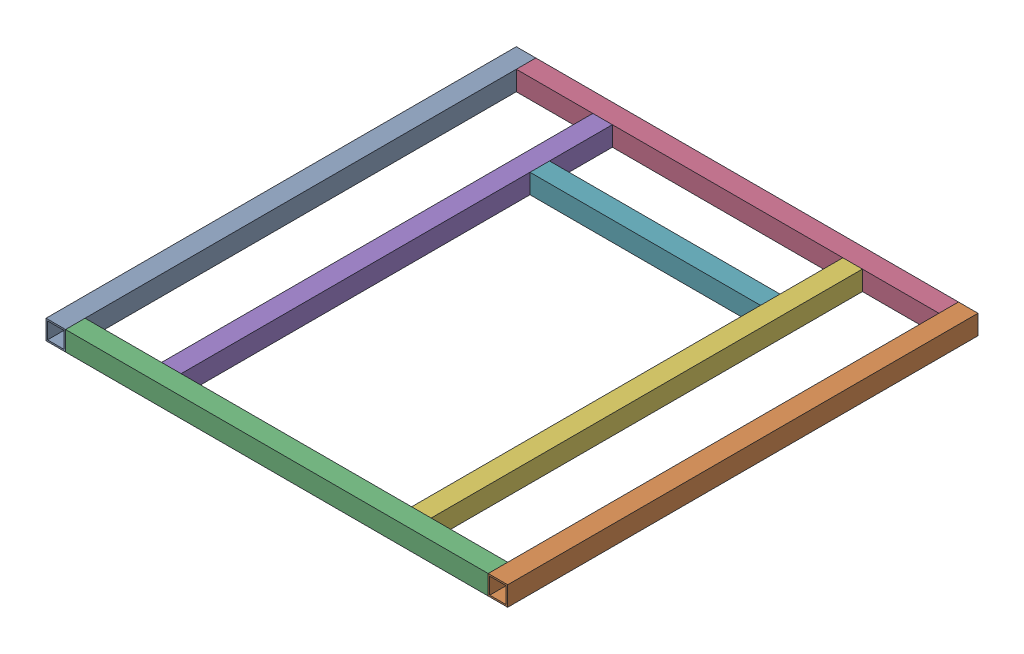
SolidWorks assembly Chassis_2_Frame_Assy, configuration Default. Lengths in mm.
Overall size (600.8 25.4 612).
7 component instances, 4 part files, 18 mates.
Components (placement in the parent):
- 1x1inch_612mmBeam-1: 1x1inch_612mmBeam [Default] at (-50.6735 117.5491 -53.1214) size (25.4 25.4 612)
- 1x1inch_612mmBeam-2: 1x1inch_612mmBeam [Default] at (524.7265 117.5491 -53.1214) size (25.4 25.4 612)
- 1x1inch_550mmBeam-1: 1x1inch_550mmBeam [Default] at (512.0265 117.5491 546.1786) x (0 0 -1) z (-1 0 0) size (25.4 25.4 550)
- 1x1inch_550mmBeam-2: 1x1inch_550mmBeam [Default] at (-37.9735 117.5491 -40.4214) x (0 0 1) z (1 0 0) size (25.4 25.4 550)
- 1x1inch_561.2mmBeam-1: 1x1inch_561.2mmBeam [Default] at (74.3265 117.5491 -27.7214) size (25.4 25.4 561.2)
- 1x1inch_561.2mmBeam-2: 1x1inch_561.2mmBeam [Default] at (399.7265 117.5491 -27.7214) size (25.4 25.4 561.2)
- 1x1inch_300mmBeam-1: 1x1inch_300mmBeam [Default] at (87.0265 117.5491 66.7786) x (0 0 -1) z (1 0 0) size (25.4 25.4 300)
Mates (geometry in assembly coordinates):
- Coincident17: coincident aligned: plane of 1x1inch_612mmBeam-1 through (-63.3735 104.8491 558.8786) normal (0 -1 0); plane of 1x1inch_550mmBeam-2 through (512.0265 104.8491 -53.1214) normal (0 -1 0)
- Coincident18: coincident aligned: plane of 1x1inch_612mmBeam-1 through (-50.6735 117.5491 -53.1214) normal (0 0 -1); plane of 1x1inch_550mmBeam-2 through (512.0265 130.2491 -53.1214) normal (0 0 -1)
- Coincident19: coincident anti-aligned: plane of 1x1inch_612mmBeam-1 through (-37.9735 104.8491 558.8786) normal (1 0 0); plane of 1x1inch_550mmBeam-2 through (-37.9735 117.5491 -40.4214) normal (-1 0 0)
- Coincident20: coincident aligned: plane of 1x1inch_612mmBeam-2 through (524.7265 117.5491 -53.1214) normal (0 0 -1); plane of 1x1inch_550mmBeam-2 through (512.0265 130.2491 -53.1214) normal (0 0 -1)
- Coincident21: coincident aligned: plane of 1x1inch_612mmBeam-2 through (512.0265 130.2491 558.8786) normal (0 1 0); plane of 1x1inch_550mmBeam-2 through (512.0265 130.2491 -53.1214) normal (0 1 0)
- Coincident22: coincident anti-aligned: plane of 1x1inch_612mmBeam-2 through (512.0265 104.8491 558.8786) normal (-1 0 0); plane of 1x1inch_550mmBeam-2 through (512.0265 117.5491 -40.4214) normal (1 0 0)
- Coincident23: coincident aligned: plane of 1x1inch_612mmBeam-2 through (512.0265 104.8491 558.8786) normal (0 -1 0); plane of 1x1inch_550mmBeam-1 through (-37.9735 104.8491 558.8786) normal (0 -1 0)
- Coincident24: coincident anti-aligned: plane of 1x1inch_612mmBeam-2 through (512.0265 104.8491 558.8786) normal (-1 0 0); plane of 1x1inch_550mmBeam-1 through (512.0265 117.5491 546.1786) normal (1 0 0)
- Coincident25: coincident aligned: plane of 1x1inch_612mmBeam-2 through (524.7265 117.5491 558.8786) normal (0 0 1); plane of 1x1inch_550mmBeam-1 through (-37.9735 130.2491 558.8786) normal (0 0 1)
- Coincident26: coincident aligned: plane of 1x1inch_550mmBeam-1 through (-37.9735 130.2491 558.8786) normal (0 1 0); plane of 1x1inch_553.2mmBeam-2 through (412.4265 130.2491 533.4786) normal (0 1 0)
- Coincident27: coincident anti-aligned: plane of 1x1inch_550mmBeam-2 through (512.0265 130.2491 -27.7214) normal (0 0 1); plane of 1x1inch_553.2mmBeam-2 through (399.7265 117.5491 -27.7214) normal (0 0 -1)
- Distance5: distance = 99.6 mm anti-aligned: plane of 1x1inch_553.2mmBeam-2 through (412.4265 130.2491 533.4786) normal (1 0 0); plane of 1x1inch_612mmBeam-2 through (512.0265 104.8491 558.8786) normal (-1 0 0)
- Distance6: distance = 300 mm anti-aligned: plane of 1x1inch_553.2mmBeam-1 through (87.0265 130.2491 533.4786) normal (1 0 0); plane of 1x1inch_553.2mmBeam-2 through (387.0265 130.2491 533.4786) normal (-1 0 0)
- Coincident30: coincident anti-aligned: plane of 1x1inch_550mmBeam-2 through (512.0265 130.2491 -27.7214) normal (0 0 1); plane of 1x1inch_553.2mmBeam-1 through (74.3265 117.5491 -27.7214) normal (0 0 -1)
- Coincident31: coincident aligned: plane of 1x1inch_550mmBeam-2 through (512.0265 130.2491 -53.1214) normal (0 1 0); plane of 1x1inch_553.2mmBeam-1 through (87.0265 130.2491 533.4786) normal (0 1 0)
- Coincident32: coincident: plane of 1x1inch_553.2mmBeam-2 through (387.0265 130.2491 533.4786) normal (-1 0 0); plane of 1x1inch_300mmBeam-1 through (387.0265 117.5491 66.7786) normal (1 0 0)
- Coincident33: coincident: plane of 1x1inch_553.2mmBeam-2 through (412.4265 130.2491 533.4786) normal (0 1 0); plane of 1x1inch_300mmBeam-1 through (387.0265 130.2491 79.4786) normal (0 1 0)
- Distance7: distance = 454 mm anti-aligned: plane of 1x1inch_300mmBeam-1 through (387.0265 104.8491 79.4786) normal (0 0 1); plane of 1x1inch_550mmBeam-1 through (-37.9735 130.2491 533.4786) normal (0 0 -1)
